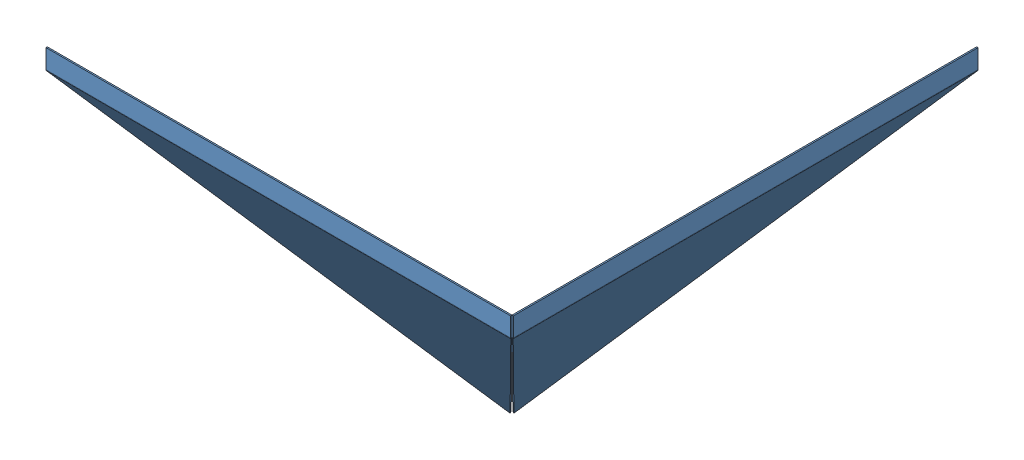
SolidWorks assembly Chute Assembly, configuration Default. Lengths in mm.
Overall size (1091.9 717.8 1091.9).
2 component instances, 1 part files, 6 mates.
Components (placement in the parent):
- Chute Side-1: Chute Side [Default] at (-533.4 -4.7302 29.581) x (1 0 0) z (0 -0.615661 0.788011) size (1066.82 887.22 30.32)
- Chute Side-2: Chute Side [Default] at (32.756 -4.7302 -536.575) x (0 0 -1) z (0.788011 -0.615661 0) size (1066.82 887.22 30.32)
Mates (geometry in assembly coordinates):
- Coincident1: coincident aligned: plane of Chute Side-1 through (-533.4 0 0) normal (0 0 1); plane of assembly through (0 0 0) normal (0 0 1)
- Coincident2: coincident aligned: plane of Chute Side-1 through (-1066.8 0 0) normal (0 1 0); plane of assembly through (0 0 0) normal (0 1 0)
- Coincident3: coincident aligned: plane of Chute Side-1 through (0 0 0) normal (1 0 0); plane of assembly through (0 0 0) normal (1 0 0)
- Coincident4: coincident anti-aligned: line of Chute Side-1 through (0 -43.815 -3.175) axis (0 1 0); line of Chute Side-2 through (0 0 -3.175) axis (0 -1 0)
- Coincident5: coincident: point of Chute Side-1; point of Chute Side-2
- Perpendicular1: perpendicular: line of Chute Side-1 through (0 0 -3.175) axis (-1 0 0); line of Chute Side-2 through (0 0 -1069.975) axis (0 0 1)
